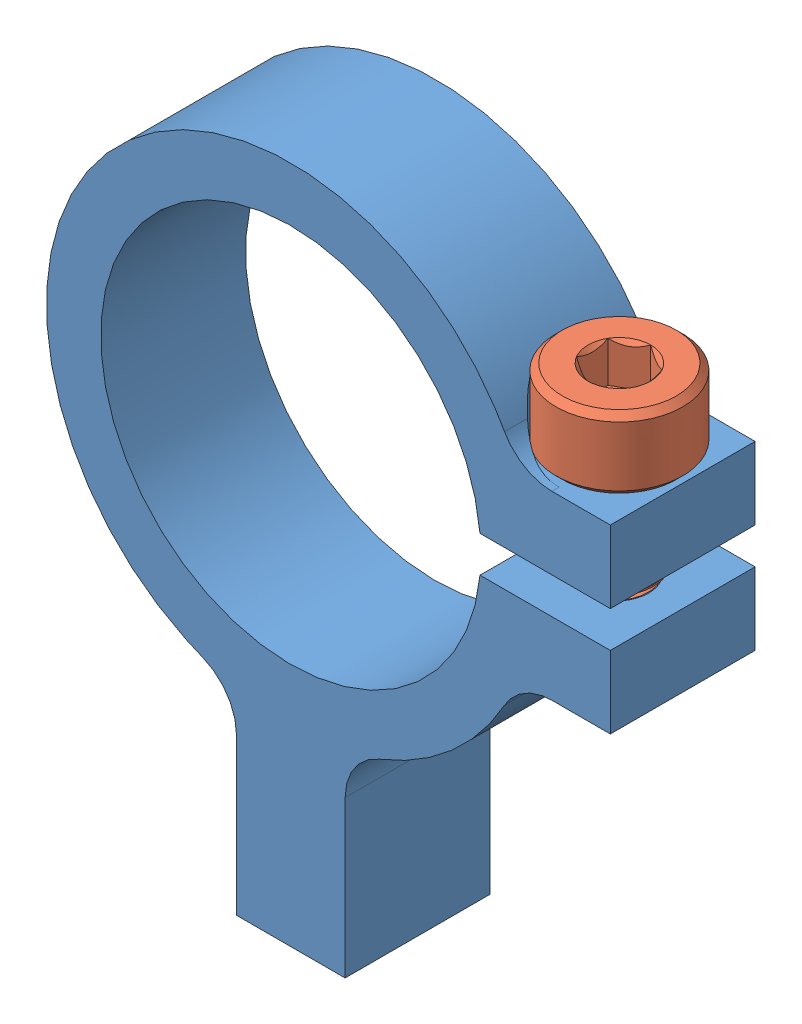
SolidWorks assembly 1-Side, 1-Post Clamping Mount (21mm Bore) 1403-0024-0021, configuration Default. Lengths in mm.
Overall size (31.15 37.5 8).
2 component instances, 2 part files, 0 mates.
Components (placement in the parent):
- 1403-0024-0021 without hardware.step-1: 1403-0024-0021 without hardware.step [Default] at (-11.9698 -1.5581 -5.8222) size (31.15 37.5 8)
- 2800-0004-0010.step-1: 2800-0004-0010.step [Default] at (2.1825 -6.5581 -1.8222) size (7 14.01 7)
